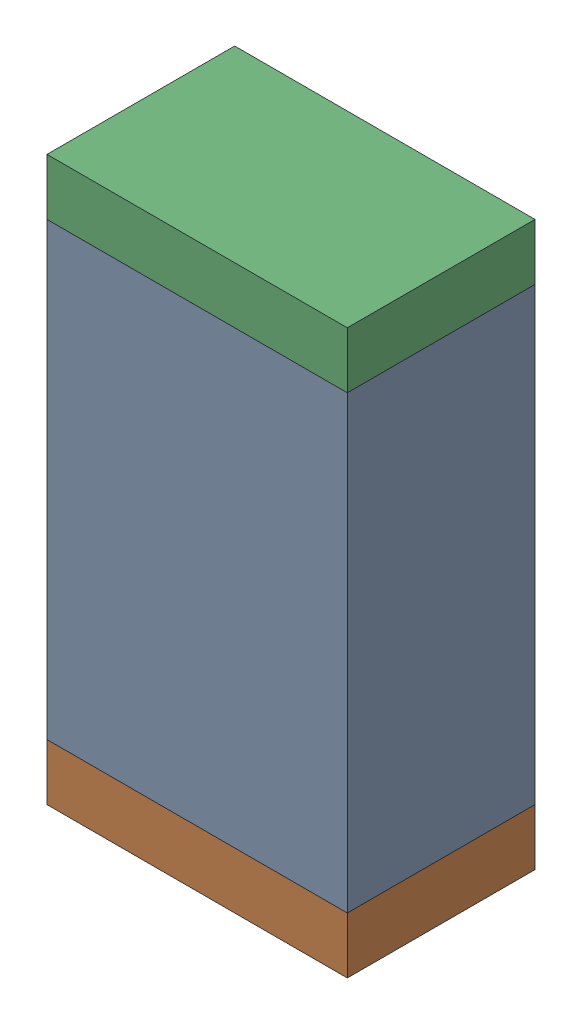
SolidWorks assembly L17, configuration Default. Lengths in mm.
Overall size (0.8 1.5 0.5).
6 component instances, 2 part files, 0 mates.
Components (placement in the parent):
- 810156976-1: 810156976 [Default] at (134.2 63.45 0) size (0.8 1.2 0.5)
  - Extruded_6-1: Extruded_6 [Default] at origin size (0.8 1.2 0.5)
- 810156592-1: 810156592 [Default] at (134.2 62.775 0) size (0.8 0.15 0.5)
  - Extruded_7-1: Extruded_7 [Default] at origin size (0.8 0.15 0.5)
- 810156592-2: 810156592 [Default] at (134.2 64.125 0) size (0.8 0.15 0.5)
  - Extruded_7-1: Extruded_7 [Default] at origin size (0.8 0.15 0.5)
